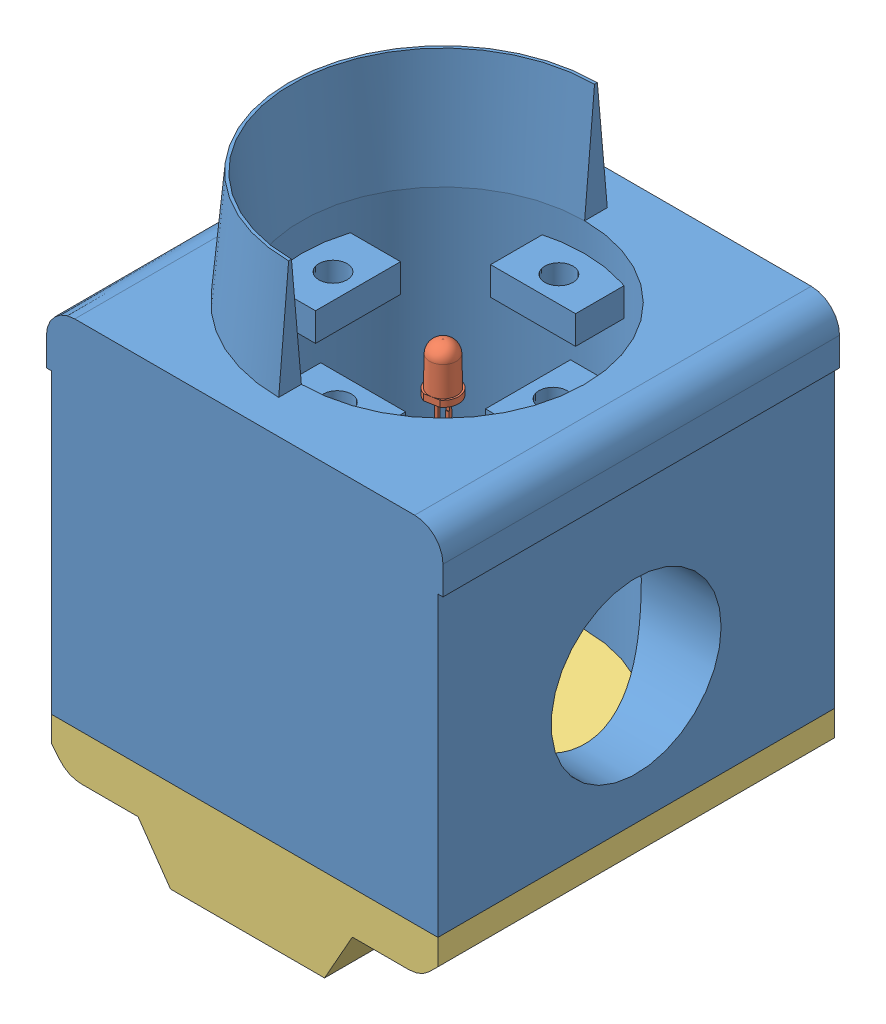
SolidWorks assembly TrafficLightAssem, configuration Default. Lengths in mm.
Overall size (70 98.71 70).
3 component instances, 3 part files, 7 mates.
Components (placement in the parent):
- Body2-1: Body2 [Default] at (-44.4823 8.0715 -33.3061) size (70 82.5 70)
- LED 5mm-1: LED 5mm [Default] at (-17.3637 18.1433 1.6939) x (-0.183633 0 -0.982995) z (0.982995 0 -0.183633) size (5.2 36.5 5.5)
- Body1-1: Body1 [Default] at (-44.4823 8.0715 -33.3061) size (68.2 16.21 70)
Mates (geometry in assembly coordinates):
- Concentric1: concentric: cylinder of Body2-1 through (-17.3637 -38.2694 1.6939) axis (0 1 0) radius 2.5; cone of LED 5mm-1 through (-17.3637 19.2433 1.6939) axis (0 1 0)
- Concentric2: concentric: circle of Body2-1; circle of LED 5mm-1
- Coincident1: coincident: plane of Body2-1 through (-17.3637 19.2433 1.6939) normal (0 -1 0); plane of LED 5mm-1 through (-17.3637 19.2433 1.6939) normal (0 1 0)
- Coincident6: coincident anti-aligned: plane of Body2-1 through (16.7356 -30.2567 36.7039) normal (0 -1 0); plane of Body1-1 through (16.7356 -30.2567 36.7039) normal (0 1 0)
- Coincident7: coincident anti-aligned: plane of Body2-1 through (16.7356 -30.2567 36.7039) normal (0 -1 0); plane of Body1-1 through (16.7356 -30.2567 36.7039) normal (0 1 0)
- Coincident8: coincident aligned: circle of Body2-1; circle of Body1-1
- Coincident9: coincident aligned: circle of Body2-1; circle of Body1-1
